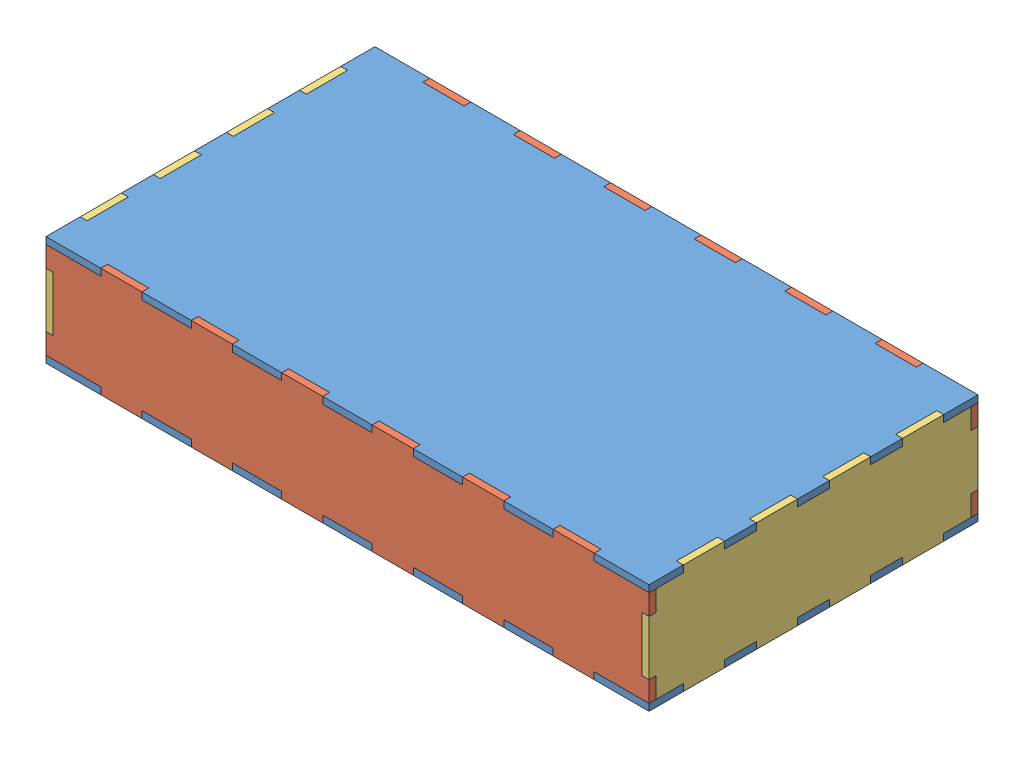
SolidWorks assembly ParametricBox_Assembly, configuration Default. Lengths in mm.
Overall size (279.4 50.8 152.4).
6 component instances, 3 part files, 16 mates.
Components (placement in the parent):
- ParametricBox_Bottom-1: ParametricBox_Bottom [Default] at origin size (279.4 3.17 152.4)
- ParametricBox_Side-1: ParametricBox_Side [Default] at (0 0 -152.4) x (1 0 0) z (0 -1 0) size (279.4 3.17 50.8)
- ParametricBox_End-1: ParametricBox_End [Default] at (279.4 0 0) x (0 1 0) z (0 0 1) size (50.8 3.17 152.4)
- ParametricBox_End-2: ParametricBox_End [Default] at (0 50.8 0) x (0 -1 0) z (0 0 1) size (50.8 3.17 152.4)
- ParametricBox_Side-2: ParametricBox_Side [Default] at (0 50.8 0) x (1 0 0) z (0 1 0) size (279.4 3.17 50.8)
- ParametricBox_Bottom-2: ParametricBox_Bottom [Default] at (0 47.625 0) size (279.4 3.17 152.4)
Mates (geometry in assembly coordinates):
- Coincident2: coincident aligned: plane of ParametricBox_Bottom-1 through (0 3.175 0) normal (-1 0 0); plane of ParametricBox_Side-1 through (0 0 -149.225) normal (-1 0 0)
- Coincident6: coincident aligned: plane of ParametricBox_Side-1 through (279.4 0 -149.225) normal (1 0 0); plane of ParametricBox_End-1 through (279.4 0 -152.4) normal (1 0 0)
- Coincident7: coincident aligned: plane of ParametricBox_Side-1 through (0 50.8 -152.4) normal (0 0 -1); plane of ParametricBox_End-1 through (276.225 0 -152.4) normal (0 0 -1)
- Coincident8: coincident aligned: plane of ParametricBox_Bottom-1 through (0 3.175 -152.4) normal (0 0 -1); plane of ParametricBox_Side-1 through (0 50.8 -152.4) normal (0 0 -1)
- Coincident9: coincident aligned: plane of ParametricBox_Bottom-1 through (279.4 3.175 0) normal (1 0 0); plane of ParametricBox_End-1 through (279.4 0 -152.4) normal (1 0 0)
- Coincident10: coincident aligned: plane of ParametricBox_Side-1 through (0 0 -149.225) normal (-1 0 0); plane of ParametricBox_End-2 through (0 50.8 -152.4) normal (-1 0 0)
- Coincident11: coincident aligned: plane of ParametricBox_Side-1 through (0 50.8 -152.4) normal (0 0 -1); plane of ParametricBox_End-2 through (3.175 50.8 -152.4) normal (0 0 -1)
- Coincident12: coincident aligned: plane of ParametricBox_Side-1 through (0 0 -149.225) normal (0 -1 0); plane of ParametricBox_End-2 through (3.175 0 0) normal (0 -1 0)
- Coincident13: coincident aligned: plane of ParametricBox_End-2 through (3.175 50.8 0) normal (0 0 1); plane of ParametricBox_Side-2 through (0 0 0) normal (0 0 1)
- Coincident14: coincident aligned: plane of ParametricBox_End-2 through (0 50.8 -152.4) normal (-1 0 0); plane of ParametricBox_Side-2 through (0 50.8 -3.175) normal (-1 0 0)
- Coincident15: coincident aligned: plane of ParametricBox_End-2 through (3.175 0 0) normal (0 -1 0); plane of ParametricBox_Side-2 through (0 0 -3.175) normal (0 -1 0)
- Coincident16: coincident aligned: plane of ParametricBox_Bottom-1 through (0 0 -152.4) normal (0 -1 0); plane of ParametricBox_Side-1 through (0 0 -149.225) normal (0 -1 0)
- Coincident17: coincident aligned: plane of ParametricBox_Side-1 through (0 0 -149.225) normal (0 -1 0); plane of ParametricBox_End-1 through (276.225 0 0) normal (0 -1 0)
- Coincident18: coincident aligned: plane of ParametricBox_Side-2 through (0 0 0) normal (0 0 1); plane of ParametricBox_Bottom-2 through (0 50.8 0) normal (0 0 1)
- Coincident19: coincident aligned: plane of ParametricBox_End-2 through (0 50.8 -152.4) normal (-1 0 0); plane of ParametricBox_Bottom-2 through (0 50.8 0) normal (-1 0 0)
- Coincident20: coincident aligned: plane of ParametricBox_End-2 through (3.175 50.8 0) normal (0 1 0); plane of ParametricBox_Bottom-2 through (0 50.8 -152.4) normal (0 1 0)
